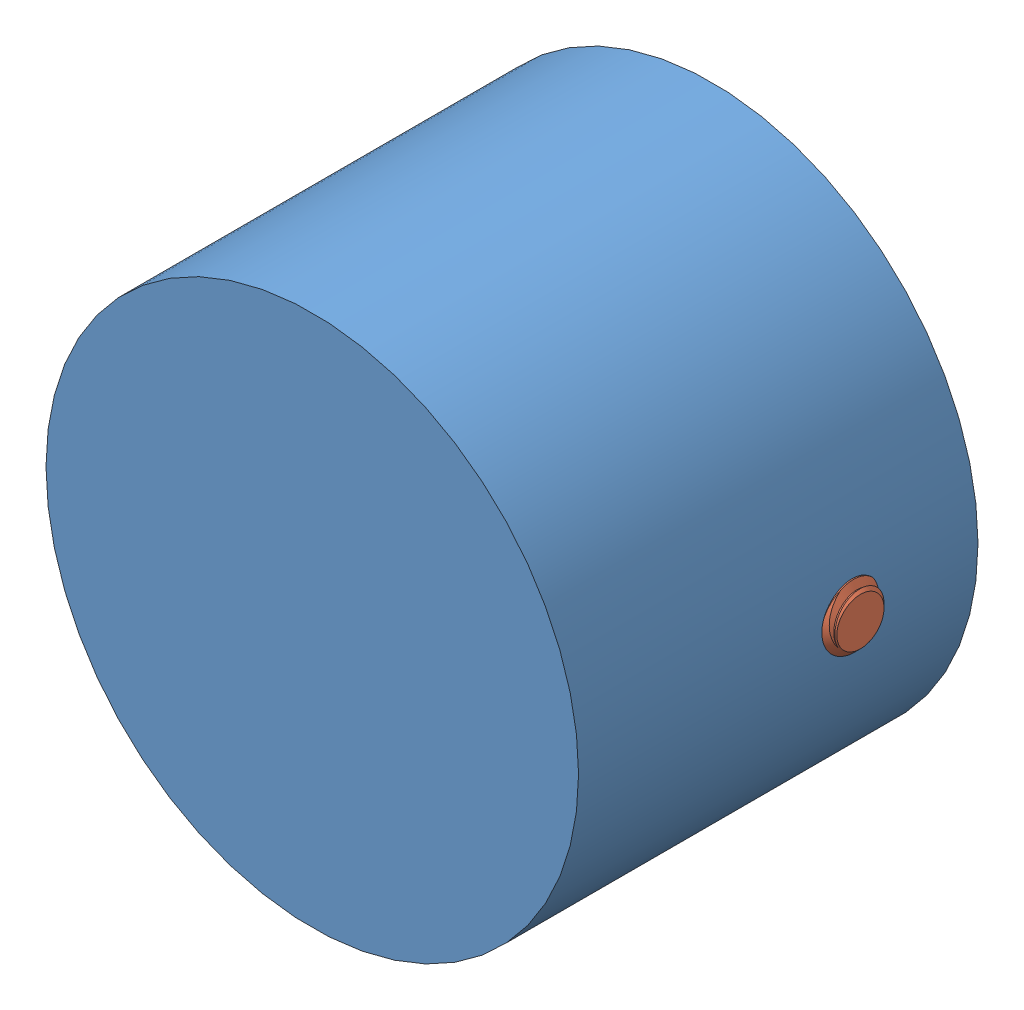
SolidWorks assembly Capture, configuration Default. Lengths in mm.
Overall size (31.46 31.46 19.05).
4 component instances, 3 part files, 8 mates.
Components (placement in the parent):
- Capture-1: Capture [Default] at origin size (25.4 25.4 19.05)
- 97493A111_ METRIC PARTIALLY THREADED STUDS-1: 97493A111_ METRIC PARTIALLY THREADED STUDS [97493A111] at (-9.525 0 -13.0175) x (0 -0.924225 -0.381849) z (1 0 0) size (3.47 3.06 6.16)
- 97493A111_ METRIC PARTIALLY THREADED STUDS-2: 97493A111_ METRIC PARTIALLY THREADED STUDS [97493A111] at (9.525 0 -13.0175) x (0 0.924225 0.381849) z (-1 0 0) size (3.47 3.06 6.16)
- 9452K720_OIL-RESISTANT BUNA-N MULTIPURPOSE O-RING-1: 9452K720_OIL-RESISTANT BUNA-N MULTIPURPOSE O-RING [9452K72] at (0 0 -16.5989) x (0.645398 -0.763847 0) z (0 0 1) size (22.33 22.33 1.78)
Mates (geometry in assembly coordinates):
- Concentric1: concentric aligned: cylinder of Capture-1 through (-12.7 0 -13.0175) axis (1 0 0) radius 1.2446; cylinder of 97493A112_ METRIC PARTIALLY THREADED STUDS-1 through (5.403 15.6924 11.9951) axis (1 0 0) radius 1.5
- Concentric2: concentric aligned: cylinder of Capture-1 through (-12.7 0 -13.0175) axis (1 0 0) radius 1.2446; cylinder of 97493A111_ METRIC PARTIALLY THREADED STUDS-1 through (-7.125 0 -13.0175) axis (1 0 0) radius 1.5
- Tangent1: tangent aligned: cylinder of Capture-1 through (0 0 -19.05) axis (0 0 1) radius 9.525; plane of 97493A111_ METRIC PARTIALLY THREADED STUDS-1 through (-9.525 0 -13.0175) normal (-1 0 0)
- Coincident1: coincident aligned: plane of Capture-1 through (0 0 0) normal (0 0 1)
- Coincident2: coincident aligned: plane of Capture-1 through (0 0 0) normal (1 0 0)
- Coincident3: coincident aligned: plane of Capture-1 through (0 0 0) normal (0 1 0)
- Concentric4: concentric: cylinder of Capture-1 through (0 0 -19.05) axis (0 0 1) radius 12.7; line of 9452K720_OIL-RESISTANT BUNA-N MULTIPURPOSE O-RING-1 through (12.1228 15.7318 -51.8542) axis (0 0 -1)
- Coincident5: coincident anti-aligned: plane of 9452K720_OIL-RESISTANT BUNA-N MULTIPURPOSE O-RING-1 through (0 0 -16.5989) normal (0 0 1)
